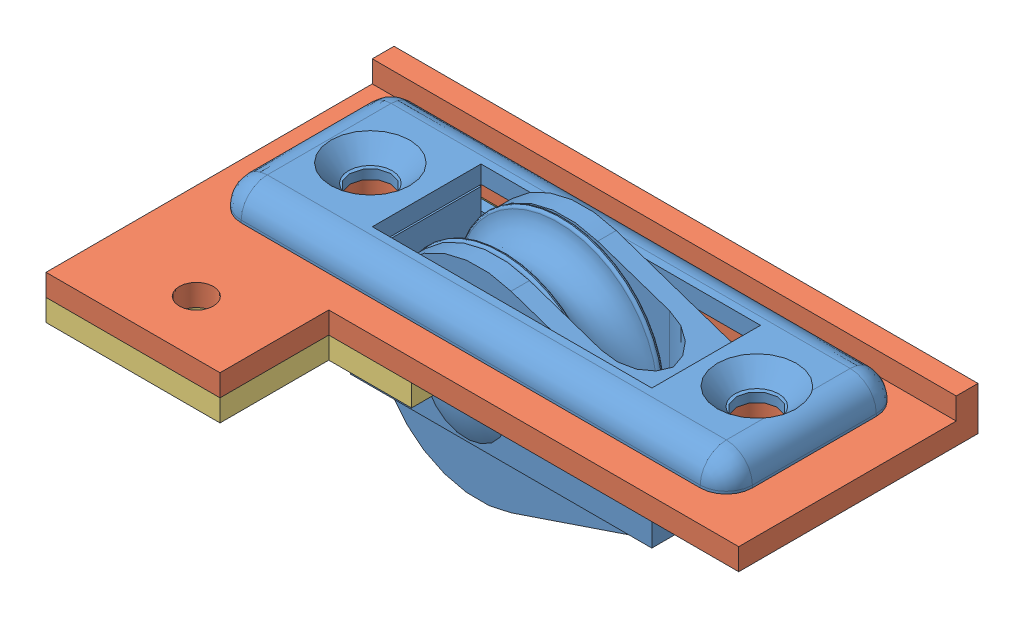
SolidWorks assembly 20-800, configuration Top. Lengths in mm.
Overall size (85.24 29.82 50.8).
3 component instances, 3 part files, 8 mates.
Components (placement in the parent):
- 20-801 Pulley 29mm-1: 20-801 Pulley 29mm [Default] at (19.4037 44.7299 47.7587) size (74.63 29.82 25.7)
- 20-802-1: 20-802 [Rev 1.1] at (19.4037 52.8579 47.7587) x (-1 0 0) z (0 -1 0) size (85.24 50.8 6.35)
- 20-804-1: 20-804 [Rev 1.1] at (19.4037 49.6829 47.7587) x (-1 0 0) z (0 -1 0) size (37.48 50.8 3.17)
Mates (geometry in assembly coordinates):
- InPlace1: in place: plane of 20-801 Pulley 29mm-1 through (19.4037 52.8579 42.8311) normal (0 -1 0); plane of ? through (0 52.8579 0) normal (0 -1 0); moOrthogonalPlaneRef_w of 20-801 Pulley 29mm-1 through (19.4037 52.8579 42.8311) normal (0 -1 0); plane of ? through (0 52.8579 0) normal (0 0 -1); plane of 20-801 Pulley 29mm-1 through (19.4037 52.8579 42.8311) normal (0 -1 0); plane of ? through (0 52.8579 0) normal (-1 0 0); plane of 20-801 Pulley 29mm-1 through (19.4037 52.8579 42.8311) normal (0 -1 0); unknown of 20-802-1
- Coincident1: coincident aligned: plane of 20-801 Pulley 29mm-1; plane of 20-802-1
- Coincident2: coincident aligned: moOrthogonalPlaneRef_w of 20-801 Pulley 29mm-1 through (19.4037 52.8579 47.7587) normal (0 0 -1); plane of 20-802-1 through (19.4037 52.8579 47.7587) normal (0 0 -1)
- Coincident3: coincident anti-aligned: moOrthogonalPlaneRef_w of 20-801 Pulley 29mm-1 through (19.4037 52.8579 47.7587) normal (1 0 0); plane of 20-802-1 through (19.4037 52.8579 47.7587) normal (-1 0 0)
- InPlace2: in place: plane of 20-802-1 through (19.4037 49.6829 47.7587) normal (0 -1 0); plane of ? through (0 49.6829 0) normal (0 -1 0); plane of 20-802-1 through (19.4037 49.6829 47.7587) normal (0 -1 0); plane of ? through (0 49.6829 0) normal (0 0 -1); plane of 20-802-1 through (19.4037 49.6829 47.7587) normal (0 -1 0); plane of ? through (0 49.6829 0) normal (-1 0 0); plane of 20-802-1 through (19.4037 49.6829 47.7587) normal (0 -1 0); unknown of 20-804-1
- Coincident1: coincident aligned: plane of 20-802-1; plane of 20-804-1
- Coincident2: coincident aligned: moOrthogonalPlaneRef_w of 20-802-1 through (19.4037 49.6829 47.7587) normal (0 0 -1); plane of 20-804-1 through (19.4037 49.6829 47.7587) normal (0 0 -1)
- Coincident3: coincident anti-aligned: moOrthogonalPlaneRef_w of 20-802-1 through (19.4037 49.6829 47.7587) normal (1 0 0); plane of 20-804-1 through (19.4037 49.6829 47.7587) normal (-1 0 0)
